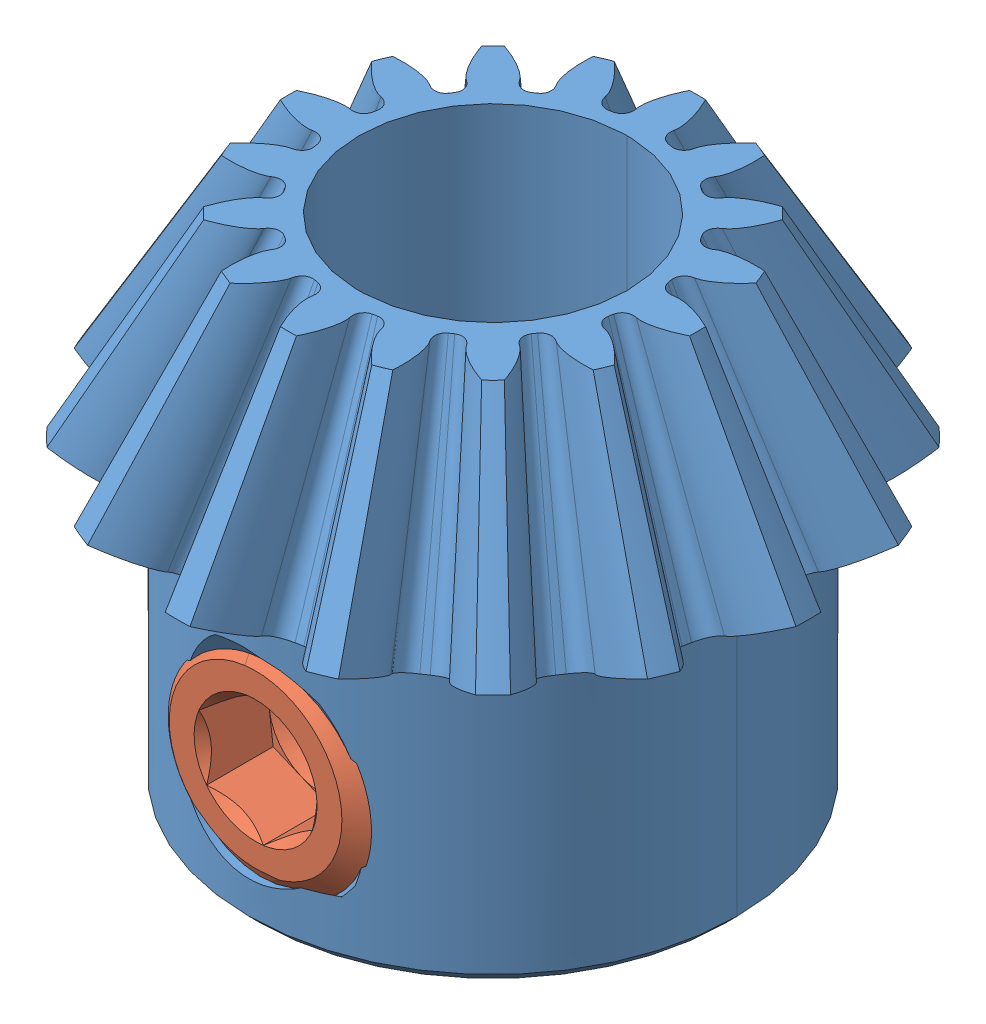
SolidWorks assembly 615440 assembly.STEP, configuration Default. Lengths in mm.
Overall size (14.16 11.54 14.16).
2 component instances, 2 part files, 0 mates.
Components (placement in the parent):
- 615440.STEP-1: 615440.STEP [Default] at (-36.6478 -2.1427 21.2524) size (14.16 11.54 14.16)
- 632134_91375A436.STEP-1: 632134_91375A436.STEP [Default] at (-36.6478 -5.5872 25.3713) x (0.992187 0.124757 0) z (0 0 1) size (4.83 4.83 3.18)
